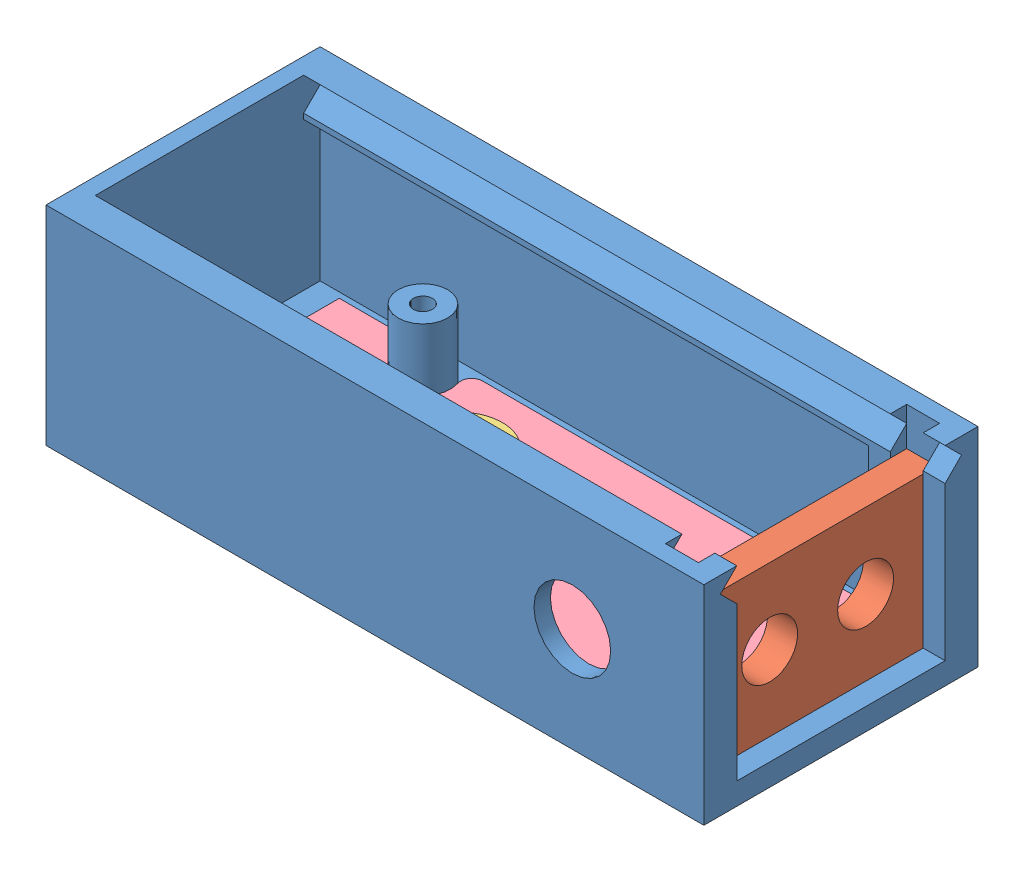
SolidWorks assembly FlashlightAssem, configuration Default. Lengths in mm.
Overall size (60 19 25).
6 component instances, 5 part files, 14 mates.
Components (placement in the parent):
- FlashlightBase-1: FlashlightBase [Default] at origin size (60 19 25)
- LEDInsert-1: LEDInsert [Default] at (25.25 8.875 0.125) x (0 -1 0) z (0 0 1) size (13.75 2.75 21.75)
- FlashlightTop V2-1: FlashlightTop V2 [Default] at (0.5 16 0) size (58 2.75 21.75) (hidden)
- FlashlightConeInsert-1: FlashlightConeInsert [Default] at (-15 11 -6.875) x (-0.874067 0 -0.485806) z (-0.485806 0 0.874067) size (8 7.5 8) (hidden)
- FlashlightConeInsert-2: FlashlightConeInsert [Default] at (0 11 4.875) x (-0.834603 0 -0.550852) z (-0.550852 0 0.834603) size (8 7.5 8)
- SampleFlashlightPCB-1: SampleFlashlightPCB [Default] at (0.25 2 0) size (50 1.5 18)
Mates (geometry in assembly coordinates):
- Coincident1: coordinate: point of FlashlightBase-1
- Coincident3: coincident anti-aligned: plane of FlashlightBase-1 through (0 2 0) normal (0 1 0); plane of LEDInsert-1 through (28 2 11) normal (0 -1 0)
- Coincident4: coincident anti-aligned: plane of FlashlightBase-1 through (28 16 11) normal (0 0 -1); plane of LEDInsert-1 through (28 15.75 11) normal (0 0 1)
- Coincident5: coincident anti-aligned: plane of FlashlightBase-1 through (28 16 11) normal (-1 0 0); plane of LEDInsert-1 through (28 8.875 0.125) normal (1 0 0)
- Coincident6: coincident anti-aligned: plane of FlashlightBase-1 through (-31.8541 17.5 11) normal (0 0.707107 -0.707107); plane of FlashlightTop V2-1 through (-28.5 11.25 4.75) normal (0 -0.707107 0.707107)
- Coincident7: coincident anti-aligned: plane of FlashlightBase-1 through (-28.5 16 -11) normal (1 0 0); plane of FlashlightTop V2-1 through (-28.5 18.75 10.875) normal (-1 0 0)
- Coincident8: coincident: line of FlashlightBase-1 through (28 16 9.5) axis (1 0 0); plane of FlashlightTop V2-1 through (0.5 16 0) normal (0 -1 0)
- Concentric1: concentric anti-aligned: cylinder of FlashlightBase-1 through (-15 9 -6.875) axis (0 -1 0) radius 2.25; cylinder of FlashlightConeInsert-1 through (-15 -13.3137 -6.875) axis (0 1 0) radius 2.75
- Concentric2: concentric anti-aligned: cylinder of FlashlightBase-1 through (0 9 4.875) axis (0 -1 0) radius 2.5; cylinder of FlashlightConeInsert-2 through (0 9 4.875) axis (0 1 0) radius 4
- Coincident9: coincident anti-aligned: plane of FlashlightBase-1 through (0 2 0) normal (0 1 0); plane of SampleFlashlightPCB-1 through (0.25 2 0) normal (0 -1 0)
- Coincident10: coincident anti-aligned: plane of FlashlightBase-1 through (0 9 4.875) normal (0 1 0); plane of FlashlightConeInsert-2 through (0 9 4.875) normal (0 -1 0)
- Coincident11: coincident anti-aligned: plane of FlashlightBase-1 through (-15 9 -6.875) normal (0 1 0); plane of FlashlightConeInsert-1 through (-15 9 -6.875) normal (0 -1 0)
- Coincident12: coincident aligned: plane of FlashlightBase-1 through (0 0 0) normal (0 0 1); plane of SampleFlashlightPCB-1 through (0.25 2 0) normal (0 0 1)
- Coincident13: coincident anti-aligned: plane of LEDInsert-1 through (25.25 8.875 0.125) normal (-1 0 0); plane of SampleFlashlightPCB-1 through (25.25 3.5 9) normal (1 0 0)
